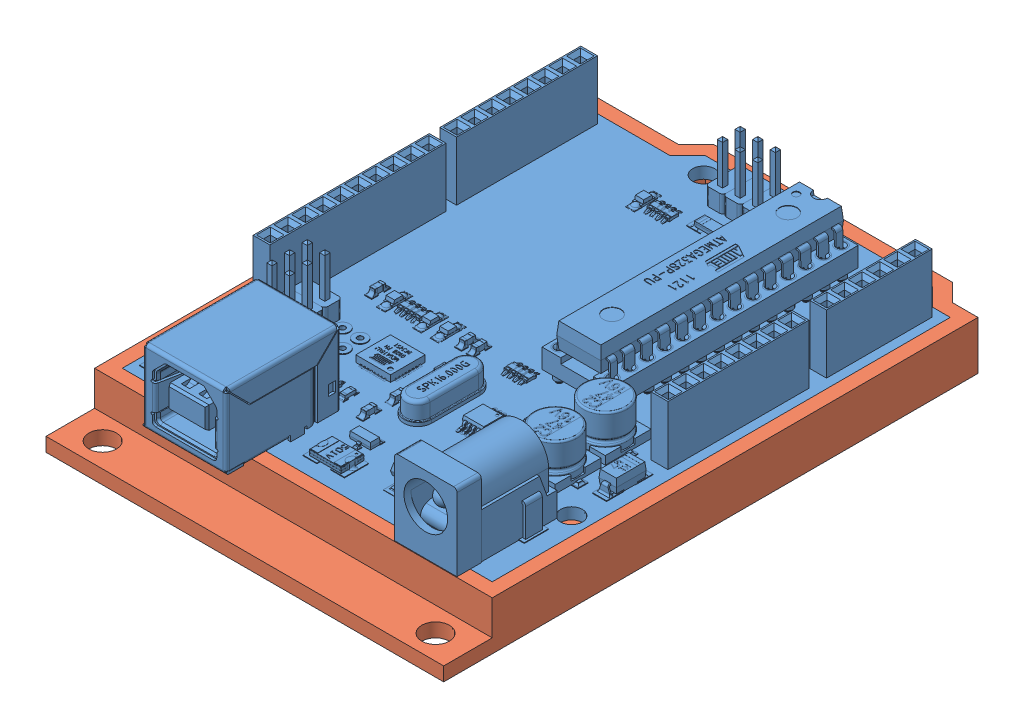
SolidWorks assembly Arduino med hållare, configuration Default. Lengths in mm.
Overall size (57.34 18.05 79.58).
2 component instances, 2 part files, 4 mates.
Components (placement in the parent):
- Arduino_uno.6df525b0-a0fc-4683-8e1a-4d70c617ad71 v1-1: Arduino_uno.6df525b0-a0fc-4683-8e1a-4d70c617ad71 v1 [Default] at (-54.8791 37.382 46.4237) size (53.34 15.25 74.93)
- Arduinohållare-1: Arduinohållare [Default] at (-54.8791 37.382 46.4237) x (1 0 0) z (0 1 0) size (57.34 79.58 7)
Mates (geometry in assembly coordinates):
- InPlace1: in place: plane of Arduino_uno.6df525b0-a0fc-4683-8e1a-4d70c617ad71 v1-1 through (-54.8791 37.382 46.4237) normal (0 1 0); plane of ? through (0 37.382 0) normal (0 1 0); moOrthogonalPlaneRef_w of Arduino_uno.6df525b0-a0fc-4683-8e1a-4d70c617ad71 v1-1 through (-54.8791 37.382 46.4237) normal (0 1 0); plane of ? through (0 37.382 0) normal (0 0 -1); plane of Arduino_uno.6df525b0-a0fc-4683-8e1a-4d70c617ad71 v1-1 through (-54.8791 37.382 46.4237) normal (0 1 0); line of ? through (-55 0 37.382) axis (0 1 0); plane of Arduino_uno.6df525b0-a0fc-4683-8e1a-4d70c617ad71 v1-1 through (-54.8791 37.382 46.4237) normal (0 1 0); unknown of Arduinohållare-1
- Coincident1: coincident aligned: plane of Arduino_uno.6df525b0-a0fc-4683-8e1a-4d70c617ad71 v1-1; plane of Arduinohållare-1
- Coincident2: coincident aligned: moOrthogonalPlaneRef_w of Arduino_uno.6df525b0-a0fc-4683-8e1a-4d70c617ad71 v1-1 through (-54.8791 37.382 46.4237) normal (0 0 -1); plane of Arduinohållare-1 through (-54.8791 37.382 46.4237) normal (0 0 -1)
- Coincident3: coincident anti-aligned: moOrthogonalPlaneRef_w of Arduino_uno.6df525b0-a0fc-4683-8e1a-4d70c617ad71 v1-1 through (-54.8791 37.382 46.4237) normal (-1 0 0); plane of Arduinohållare-1 through (-54.8791 37.382 46.4237) normal (1 0 0)
